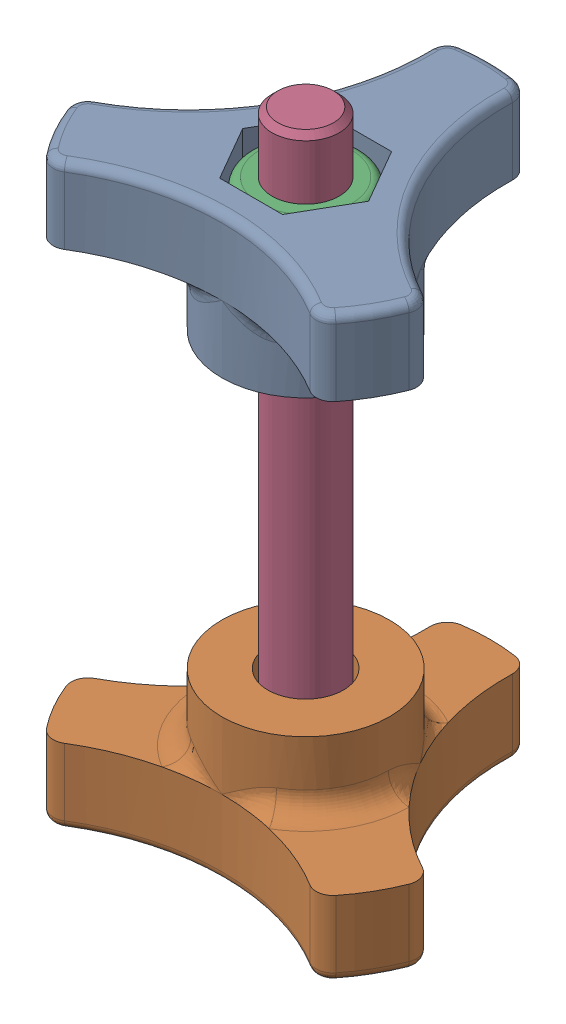
SolidWorks assembly TR23-RC-0700_35mm, configuration Default. Lengths in mm.
Overall size (41.18 75.3 36.41).
4 component instances, 4 part files, 0 mates.
Components (placement in the parent):
- TR23-RC-0050-1: TR23-RC-0050 [Default] at origin size (41.18 17 36.41)
- TR23-RC-0051-1: TR23-RC-0051 [Default] at (0 -35 0) x (-1 0 0) z (0 0 1) size (41.18 17 36.41)
- ISO 10511 M8 Locking Nut-1: ISO 10511 M8 Locking Nut [Default] at (0 9 0) x (0 0 -1) z (1 0 0) size (13 6.76 15.01)
- ISO 4017 - M8 x 70-N_ISO 4017 - M8 x 70-N-1: ISO 4017 - M8 x 70-N_ISO 4017 - M8 x 70-N [Default] at (0 -52.3 0) x (0 1 0) z (0 0 1) size (75.3 15.01 13)
